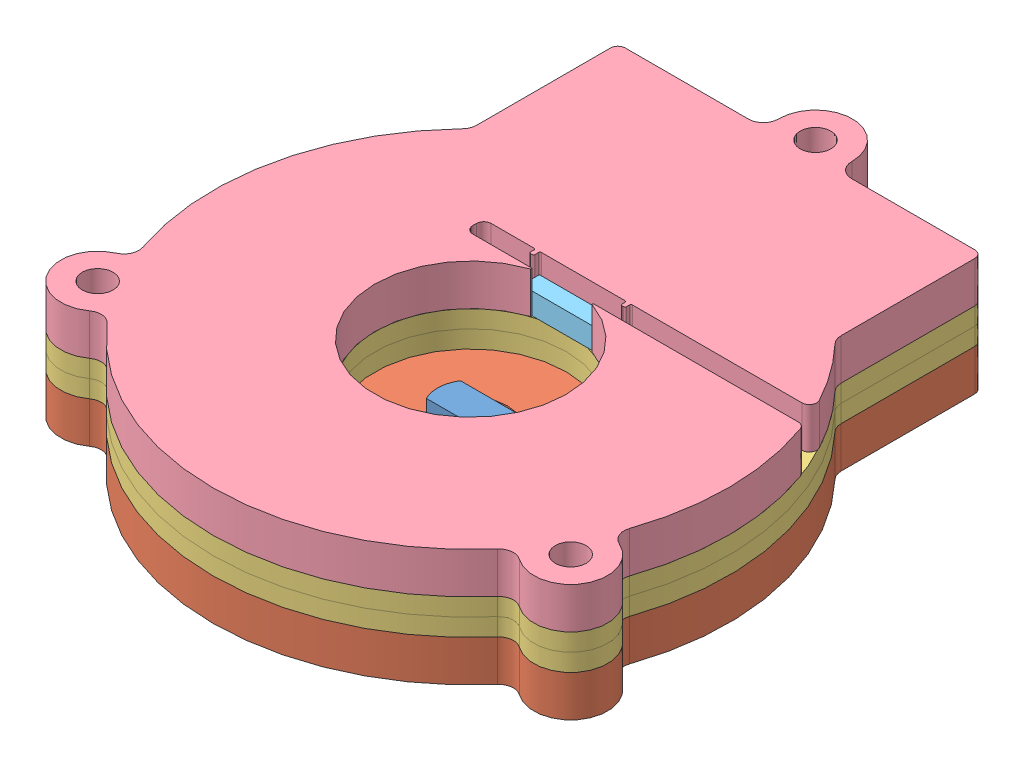
SolidWorks assembly CoverAssembly, configuration Default. Lengths in mm.
Overall size (74.28 15.94 86.84).
7 component instances, 6 part files, 13 mates.
Components (placement in the parent):
- Shaft-1: Shaft [Default] at (18.3598 14.2464 5.6737) size (9 7.94 4.4)
- NewCover220-1: NewCover220 [Default] at (18.3598 14.2464 5.6737) size (74.28 5.59 86.84)
- Magnet-1: Magnet [Default] at (18.3598 22.1835 5.6737) size (25 5.95 25) (hidden)
- NewCover093L2-5: NewCover093L2 [Default] at (18.3598 22.2156 5.6737) size (74.28 2.38 86.84)
- NewCoverMagnetSlot220-2: NewCoverMagnetSlot220 [Default] at (18.3598 24.5969 5.6737) size (74.28 5.59 86.84)
- ReedSwitch-2: ReedSwitch [Default] at (12.7825 24.5969 -6.8268) size (16.26 2.92 2.41)
- NewCover093L2-6: NewCover093L2 [Default] at (18.3598 19.8344 5.6737) size (74.28 2.38 86.84)
Mates (geometry in assembly coordinates):
- Coincident1: coincident: plane of Shaft-1 through (18.3598 14.2464 5.6737) normal (0 -1 0); plane of NewCover220-1 through (18.3598 14.2464 5.6737) normal (0 -1 0)
- Concentric1: concentric: circle of Shaft-1; circle of NewCover220-1
- Coincident3: coincident: plane of Shaft-1 through (18.3598 22.1835 5.6737) normal (0 1 0); circle of Magnet-1
- Concentric3: concentric: circle of Shaft-1; circle of Magnet-1
- Coincident4: coincident: plane of Shaft-1 through (18.3598 14.2464 5.6737) normal (0 -1 0); plane of NewCover220-1 through (18.3598 14.2464 5.6737) normal (0 -1 0)
- Coincident15: coincident: plane of NewCover093L2-5 through (18.3598 24.5969 5.6737) normal (0 1 0); plane of NewCoverMagnetSlot220-2 through (18.3598 24.5969 5.6737) normal (0 -1 0)
- Concentric7: concentric: circle of NewCover093L2-5; circle of NewCoverMagnetSlot220-2
- Concentric8: concentric: circle of NewCover093L2-5; circle of NewCoverMagnetSlot220-2
- Coincident18: coincident: plane of NewCover093L2-5 through (18.3598 24.5969 5.6737) normal (0 1 0); plane of ReedSwitch-2 through (12.7825 24.5969 -6.8268) normal (0 -1 0)
- Coincident19: coincident: plane of NewCoverMagnetSlot220-2 through (55.1437 -25.4656 -6.8268) normal (0 0 -1); plane of ReedSwitch-2 through (12.7825 27.5169 -6.8268) normal (0 0 1)
- Coincident20: coincident: plane of NewCoverMagnetSlot220-2 through (12.7825 23.5326 -9.3268) normal (1 0 0); plane of ReedSwitch-2 through (12.7825 27.5169 -6.8268) normal (-1 0 0)
- Coincident24: coincident: plane of NewCover220-1 through (18.3598 19.8344 5.6737) normal (0 1 0); plane of NewCover093L2-6 through (18.3598 19.8344 5.6737) normal (0 -1 0)
- Concentric11: concentric: circle of NewCover220-1; circle of NewCover093L2-6
